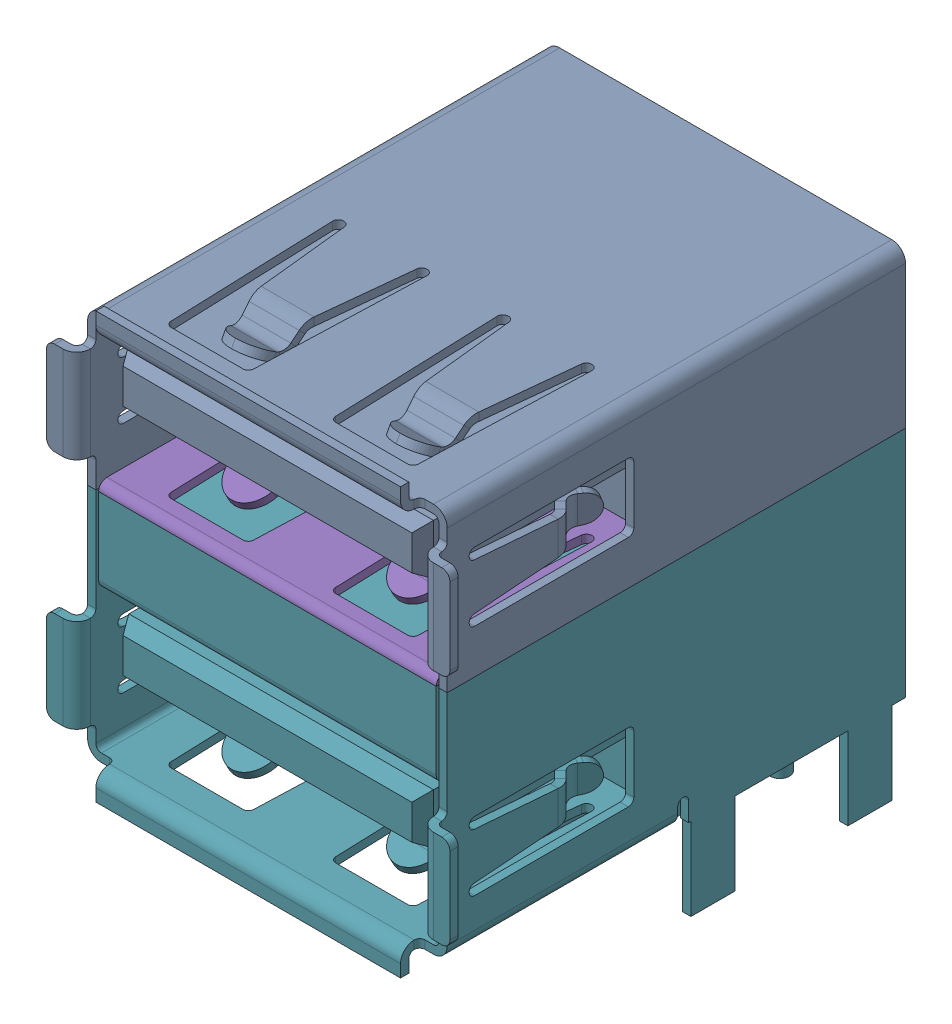
SolidWorks assembly raspberry_pi__USB_x2, configuration Default. Lengths in mm.
Overall size (14.7 17.85 17.4).
2 component instances, 2 part files, 0 mates.
Components (placement in the parent):
- raspberry_pi__USB_x2_part1_Å« Ò¼«½þá¡¿¯-1: raspberry_pi__USB_x2_part1_Å« Ò¼«½þá¡¿¯ [Default] at (-114.6616 -10.9375 -4.85) x (0 0 1) z (-1 0 0) size (17.4 6.35 14.7)
- raspberry_pi__USB_x2_part2_Å« Ò¼«½þá¡¿¯-1: raspberry_pi__USB_x2_part2_Å« Ò¼«½þá¡¿¯ [Default] at (-114.6616 -19.4375 -4.85) x (0 0 1) z (-1 0 0) size (17.4 11.5 14.7)
